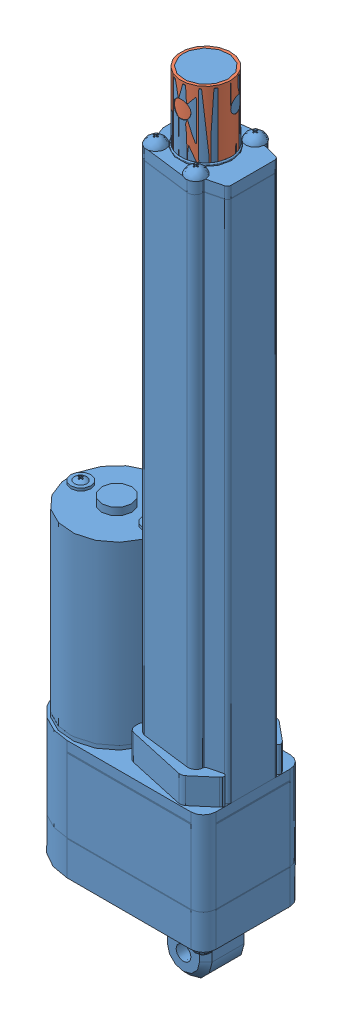
SolidWorks assembly UOR23-ARM-2-A-003_Linear_Actuator, configuration Default. Lengths in mm.
Overall size (75.05 314 40).
2 component instances, 2 part files, 2 mates.
Components (placement in the parent):
- FA-OS-35(200)-12-6-1: FA-OS-35(200)-12-6 [Default] at (103.3637 94.9071 228.4325) x (1 0 0) z (0 1 0) size (75.05 40 314)
- actuator extension-1: actuator extension [Default] at (139.3637 107.9632 228.4325) x (0.303562 0 0.952812) z (-0.952812 0 0.303562) size (19.99 228.6 19.99)
Mates (geometry in assembly coordinates):
- Concentric1: concentric aligned: circle of FA-OS-35(200)-12-6-1; circle of actuator extension-1
- LimitDistance1: limit distance = 0 mm aligned: plane of FA-OS-35(200)-12-6-1 through (139.3637 336.5632 228.4325) normal (0 1 0); plane of actuator extension-1 through (139.3637 336.5632 228.4325) normal (0 1 0)
